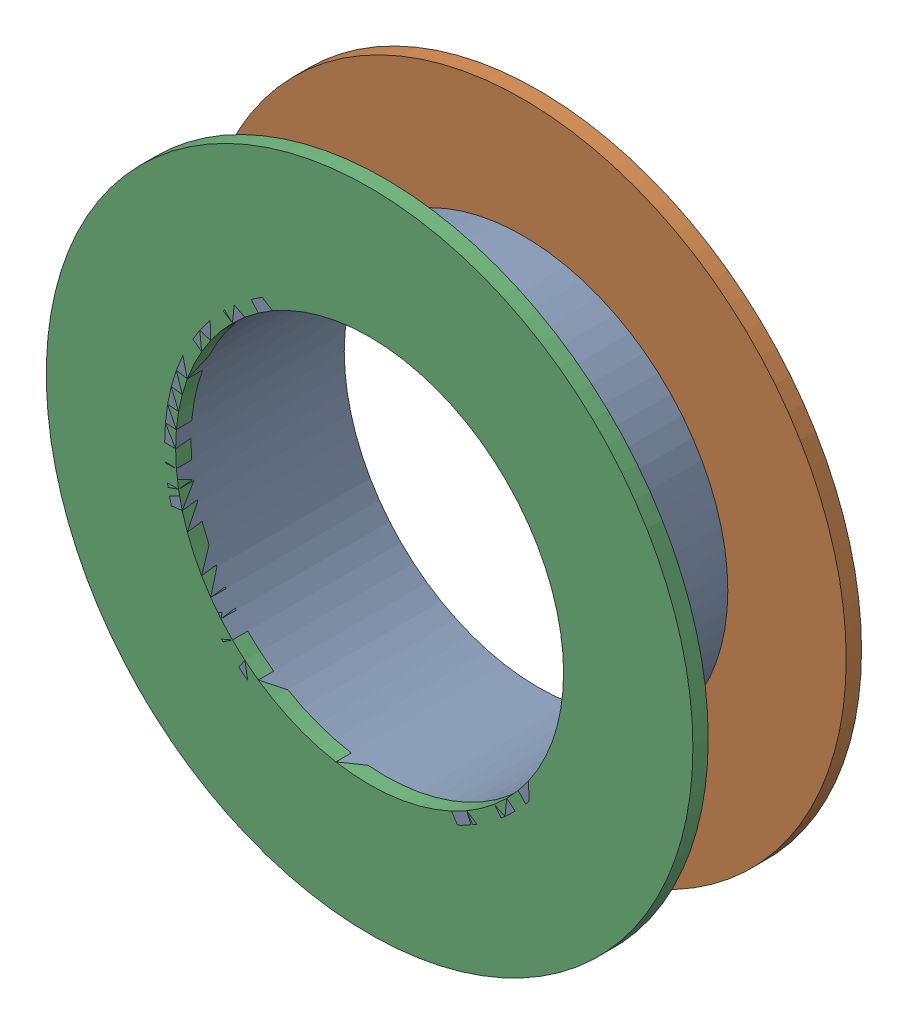
SolidWorks assembly Pad SWD-2(15.494mm,48.387mm) on Multi-Layer, configuration Predeterminado. Lengths in mm.
Overall size (1.5 1.5 0.39).
6 component instances, 2 part files, 0 mates.
Components (placement in the parent):
- Pad Hole-1-1: Pad Hole-1 [Predeterminado] at (15.494 48.387 -0.4013) size (0.95 0.95 0.39)
  - Pad Hole-Part-1-1-1: Pad Hole-Part-1-1 [Predeterminado] at origin size (0.95 0.95 0.39)
- Top Layer-1-1: Top Layer-1 [Predeterminado] at (15.494 48.387 -0.4013) size (1.5 1.5 0.04)
  - Top Layer-Part-1-1-1: Top Layer-Part-1-1 [Predeterminado] at origin size (1.5 1.5 0.04)
- Top Layer-1-2: Top Layer-1 [Predeterminado] at (15.494 48.387 -0.0457) size (1.5 1.5 0.04)
  - Top Layer-Part-1-1-1: Top Layer-Part-1-1 [Predeterminado] at origin size (1.5 1.5 0.04)
